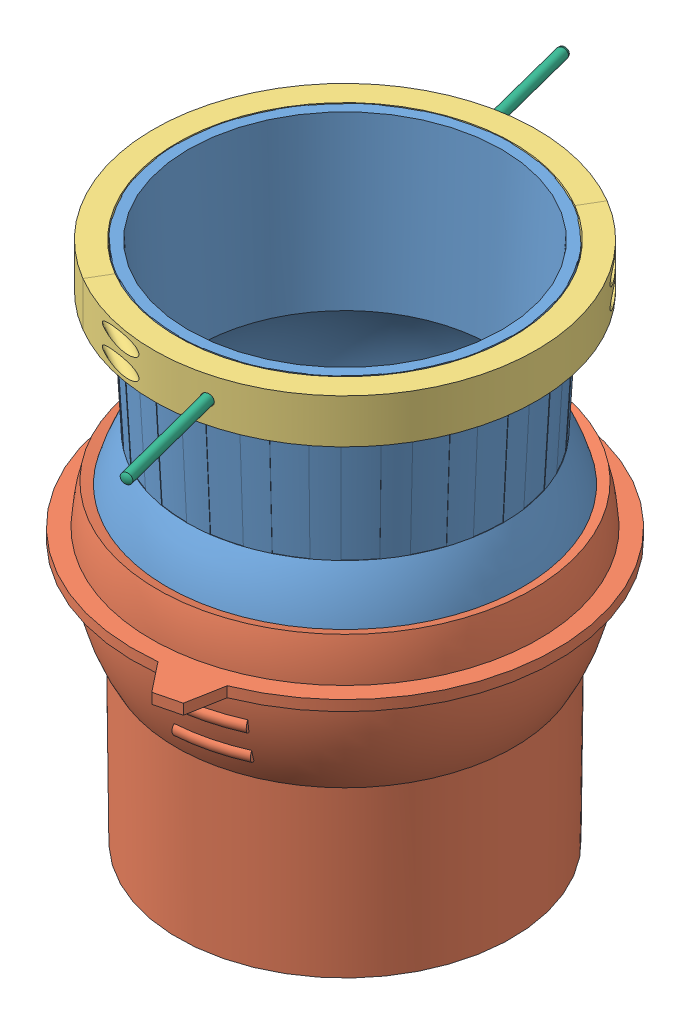
SolidWorks assembly Gimbal System_TVR_UBC Rocket, configuration Default. Lengths in mm.
Overall size (151.67 149.84 170.58).
15 component instances, 6 part files, 21 mates.
Components (placement in the parent):
- Gimbal Duct_Gimbal System_TVR_UBC Rocket-1: Gimbal Duct_Gimbal System_TVR_UBC Rocket [Default] at (29.4853 40.1703 66.7532) size (151.67 149.84 165.21)
  - Upper Gimbal Nozzle_Gimbal System_TVR_UBC Rocket-1: Upper Gimbal Nozzle_Gimbal System_TVR_UBC Rocket [Default] at (30.3053 126.7614 79.6638) size (106.04 107.12 106.04)
  - Lower Gimbal Nozzle_Gimbal System_TVR_UBC Rocket-1: Lower Gimbal Nozzle_Gimbal System_TVR_UBC Rocket [Default] at (30.3053 -23.0804 79.6638) x (-0.241922 0 -0.970296) z (-0.970296 0 0.241922) size (140 89.7 121.41)
- Gimbal Carrier_Gimbal System_TVR_UBC Rocket-1: Gimbal Carrier_Gimbal System_TVR_UBC Rocket [BOLT SIDE] at (59.7906 166.9316 146.417) x (0.509041 0 -0.860742) z (0.860742 0 0.509041) size (110 12.7 55)
- Gimbal Carrier_Gimbal System_TVR_UBC Rocket-2: Gimbal Carrier_Gimbal System_TVR_UBC Rocket [NUT SIDE] at (59.7906 166.9316 146.417) x (-0.509041 0 0.860742) z (-0.860742 0 -0.509041) size (110 12.7 55)
- 90592A075_Steel Hex Nut-1: 90592A075_Steel Hex Nut [90592A075] at (81.0776 163.5816 99.0287) x (0.509041 0 -0.860742) z (0 -1 0) size (4 1.91 4.62)
- 91290A045_Alloy Steel Socket Head Screw-1: 91290A045_Alloy Steel Socket Head Screw [91290A045] at (85.2091 163.5816 101.4721) x (0.469434 0.386728 -0.793771) z (0.860742 0 0.509041) size (3.8 3.8 16.25)
- 90592A075_Steel Hex Nut-2: 90592A075_Steel Hex Nut [90592A075] at (81.0776 157.5816 99.0287) x (0.509041 0 -0.860742) z (0 -1 0) size (4 1.91 4.62)
- 91290A045_Alloy Steel Socket Head Screw-2: 91290A045_Alloy Steel Socket Head Screw [91290A045] at (85.2091 157.5816 101.4721) x (0.509041 0 -0.860742) z (0.860742 0 0.509041) size (3.8 3.8 16.25)
- 91290A045_Alloy Steel Socket Head Screw-3: 91290A045_Alloy Steel Socket Head Screw [91290A045] at (32.4682 163.5816 190.2359) x (-0.469434 0.386728 0.793771) z (-0.860742 0 -0.509041) size (3.8 3.8 16.25)
- 91290A045_Alloy Steel Socket Head Screw-4: 91290A045_Alloy Steel Socket Head Screw [91290A045] at (32.6506 157.5816 190.3438) x (-0.509041 0 0.860742) z (0.860742 0 0.509041) size (3.8 3.8 16.25)
- 90592A075_Steel Hex Nut-3: 90592A075_Steel Hex Nut [90592A075] at (28.5191 163.5816 187.9004) x (-0.509041 0 0.860742) z (0 1 0) size (4 1.91 4.62)
- 90592A075_Steel Hex Nut-4: 90592A075_Steel Hex Nut [90592A075] at (28.5191 157.5816 187.9004) x (-0.509041 0 0.860742) z (0 1 0) size (4 1.91 4.62)
- 91595A142_Dowel Pin-1: 91595A142_Dowel Pin [91595A142] at (76.6197 160.5816 211.9616) x (0 -1 0) z (-0.24869 0 -0.968583) size (3 3 40)
- 91595A142_Dowel Pin-2: 91595A142_Dowel Pin [91595A142] at (42.9615 160.5816 80.872) x (0.968583 0 -0.24869) z (-0.24869 0 -0.968583) size (3 3 40)
Mates (geometry in assembly coordinates):
- Concentric1: concentric aligned: cone of Gimbal Duct_Gimbal System_TVR_UBC Rocket-1/Upper Gimbal Nozzle_Gimbal System_TVR_UBC Rocket-1 through (59.7906 119.2288 146.417) axis (0 -1 0); cone of Gimbal Carrier_Gimbal System_TVR_UBC Rocket-1 through (59.7906 166.9316 146.417) axis (0 -1 0)
- Coincident4: coincident aligned: plane of Gimbal Duct_Gimbal System_TVR_UBC Rocket-1/Upper Gimbal Nozzle_Gimbal System_TVR_UBC Rocket-1 through (59.7906 166.9316 101.417) normal (0 1 0); plane of Gimbal Carrier_Gimbal System_TVR_UBC Rocket-1 through (31.7934 166.9316 193.7578) normal (0 1 0)
- Concentric2: concentric aligned: cone of Gimbal Duct_Gimbal System_TVR_UBC Rocket-1/Upper Gimbal Nozzle_Gimbal System_TVR_UBC Rocket-1 through (59.7906 119.2288 146.417) axis (0 -1 0); cone of Gimbal Carrier_Gimbal System_TVR_UBC Rocket-2 through (59.7906 166.9316 146.417) axis (0 -1 0)
- Coincident6: coincident aligned: plane of Gimbal Duct_Gimbal System_TVR_UBC Rocket-1/Upper Gimbal Nozzle_Gimbal System_TVR_UBC Rocket-1 through (59.7906 166.9316 101.417) normal (0 1 0); plane of Gimbal Carrier_Gimbal System_TVR_UBC Rocket-2 through (87.7879 166.9316 99.0762) normal (0 1 0)
- Coincident7: coincident anti-aligned: plane of Gimbal Carrier_Gimbal System_TVR_UBC Rocket-1 through (59.7906 166.9316 146.417) normal (-0.860742 0 -0.509041); plane of Gimbal Carrier_Gimbal System_TVR_UBC Rocket-2 through (59.7906 166.9316 146.417) normal (0.860742 0 0.509041)
- Concentric3: concentric anti-aligned: cylinder of Gimbal Carrier_Gimbal System_TVR_UBC Rocket-1 through (133.4107 163.5816 129.9784) axis (0.860742 0 0.509041) radius 2.2; cylinder of 91290A045_Alloy Steel Socket Head Screw-1 through (78.3232 163.5816 97.3998) axis (-0.860742 0 -0.509041) radius 1.9
- Coincident8: coincident anti-aligned: plane of Gimbal Carrier_Gimbal System_TVR_UBC Rocket-1 through (90.9335 163.5816 103.5796) normal (0.860742 0 0.509041); plane of 91290A045_Alloy Steel Socket Head Screw-1 through (90.0192 165.2416 105.1255) normal (-0.860742 0 -0.509041)
- Concentric4: concentric anti-aligned: cylinder of Gimbal Carrier_Gimbal System_TVR_UBC Rocket-2 through (81.7662 163.5816 99.436) axis (-0.860742 0 -0.509041) radius 1.15; circle of 90592A075_Steel Hex Nut-1
- Parallel2: parallel anti-aligned: plane of Gimbal Carrier_Gimbal System_TVR_UBC Rocket-2 through (82.8351 162.3692 97.6284) normal (-0.509041 0 0.860742); plane of 90592A075_Steel Hex Nut-1 through (82.7842 162.4269 97.7145) normal (0.509041 0 -0.860742)
- Coincident10: coincident anti-aligned: plane of Gimbal Carrier_Gimbal System_TVR_UBC Rocket-2 through (55.4869 166.9316 143.8718) normal (-0.860742 0 -0.509041); plane of 90592A075_Steel Hex Nut-1 through (80.7481 164.7363 101.1574) normal (0.860742 0 0.509041)
- Concentric5: concentric anti-aligned: cylinder of Gimbal Carrier_Gimbal System_TVR_UBC Rocket-1 through (133.4107 157.5816 129.9784) axis (0.860742 0 0.509041) radius 2.2; cylinder of 91290A045_Alloy Steel Socket Head Screw-2 through (78.3232 157.5816 97.3998) axis (-0.860742 0 -0.509041) radius 1.9
- Coincident11: coincident anti-aligned: plane of Gimbal Carrier_Gimbal System_TVR_UBC Rocket-1 through (90.9335 157.5816 103.5796) normal (0.860742 0 0.509041); plane of 91290A045_Alloy Steel Socket Head Screw-2 through (90.3736 159.3816 104.5264) normal (-0.860742 0 -0.509041)
- Concentric6: concentric anti-aligned: cylinder of Gimbal Carrier_Gimbal System_TVR_UBC Rocket-2 through (81.7662 157.5816 99.436) axis (-0.860742 0 -0.509041) radius 1.15; circle of 90592A075_Steel Hex Nut-2
- Parallel3: parallel anti-aligned: plane of Gimbal Carrier_Gimbal System_TVR_UBC Rocket-2 through (82.8351 156.3692 97.6284) normal (-0.509041 0 0.860742); plane of 90592A075_Steel Hex Nut-2 through (82.7842 156.4269 97.7145) normal (0.509041 0 -0.860742)
- Coincident13: coincident anti-aligned: plane of Gimbal Carrier_Gimbal System_TVR_UBC Rocket-2 through (55.4869 166.9316 143.8718) normal (-0.860742 0 -0.509041); plane of 90592A075_Steel Hex Nut-2 through (80.7481 158.7363 101.1574) normal (0.860742 0 0.509041)
- Concentric8: concentric anti-aligned: cylinder of Gimbal Carrier_Gimbal System_TVR_UBC Rocket-1 through (34.9216 160.5816 49.5587) axis (0.24869 0 0.968583) radius 1.65; cylinder of 91595A142_Dowel Pin-1 through (71.6459 160.5816 192.59) axis (-0.24869 0 -0.968583) radius 1.5
- Concentric9: concentric aligned: cylinder of Gimbal Carrier_Gimbal System_TVR_UBC Rocket-2 through (84.6597 160.5816 243.2753) axis (-0.24869 0 -0.968583) radius 1.65; cylinder of 91595A142_Dowel Pin-2 through (37.9877 160.5816 61.5004) axis (-0.24869 0 -0.968583) radius 1.5
- Tangent1: tangent anti-aligned: cone of Gimbal Duct_Gimbal System_TVR_UBC Rocket-1/Upper Gimbal Nozzle_Gimbal System_TVR_UBC Rocket-1 through (59.7906 119.2288 146.417) axis (0 -1 0); sphere of 91595A142_Dowel Pin-2
- Tangent2: tangent anti-aligned: cone of Gimbal Duct_Gimbal System_TVR_UBC Rocket-1/Upper Gimbal Nozzle_Gimbal System_TVR_UBC Rocket-1 through (59.7906 119.2288 146.417) axis (0 -1 0); sphere of 91595A142_Dowel Pin-1
- Parallel5: parallel anti-aligned: plane of Gimbal Carrier_Gimbal System_TVR_UBC Rocket-2 through (87.7879 166.9316 99.0762) normal (0 1 0); plane of 91595A142_Dowel Pin-2 through (42.9615 160.5816 80.872) normal (0 -1 0)
- Parallel6: parallel anti-aligned: plane of Gimbal Carrier_Gimbal System_TVR_UBC Rocket-1 through (31.7934 166.9316 193.7578) normal (0 1 0); plane of 91595A142_Dowel Pin-1 through (76.6197 160.5816 211.9616) normal (0 -1 0)
